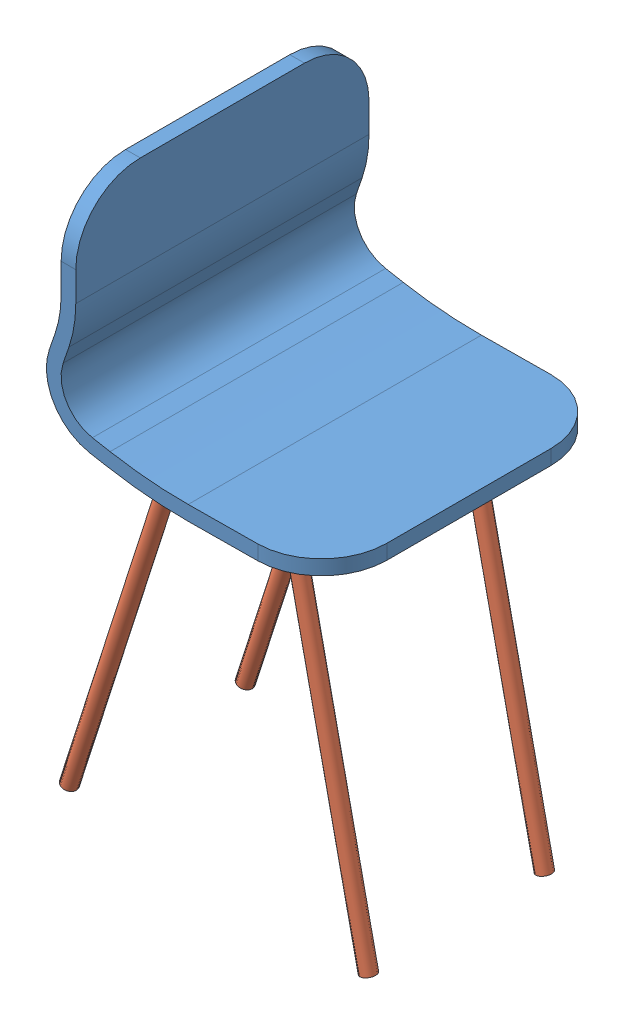
SolidWorks assembly Assem1 CHAIR, configuration Default. Lengths in mm.
Overall size (563.4 1003.15 500).
2 component instances, 2 part files, 4 mates.
Components (placement in the parent):
- CHAIR-1: CHAIR [Default] at origin size (470.76 385.84 500)
- CHAIR PART 2-1: CHAIR PART 2 [Default] at (537.5166 -90.9299 -150) x (-0.998826 0.048446 0) z (0 0 1) size (534.73 604.79 375)
Mates (geometry in assembly coordinates):
- Coincident1: coincident aligned: plane of CHAIR-1 through (0 0 0) normal (0 0 1); plane of assembly through (0 0 0) normal (0 0 1)
- Coincident2: coincident aligned: plane of CHAIR-1 through (0 0 0) normal (0 1 0); plane of assembly through (0 0 0) normal (0 1 0)
- Coincident3: coincident aligned: plane of CHAIR-1 through (0 0 0) normal (1 0 0); plane of assembly through (0 0 0) normal (1 0 0)
- Tangent1: tangent anti-aligned: cylinder of CHAIR-1 through (550.835 671.3199 250) axis (0 0 -1) radius 740; plane of CHAIR PART 2-1 through (538.5824 -68.9557 150) normal (0.048446 0.998826 0)
